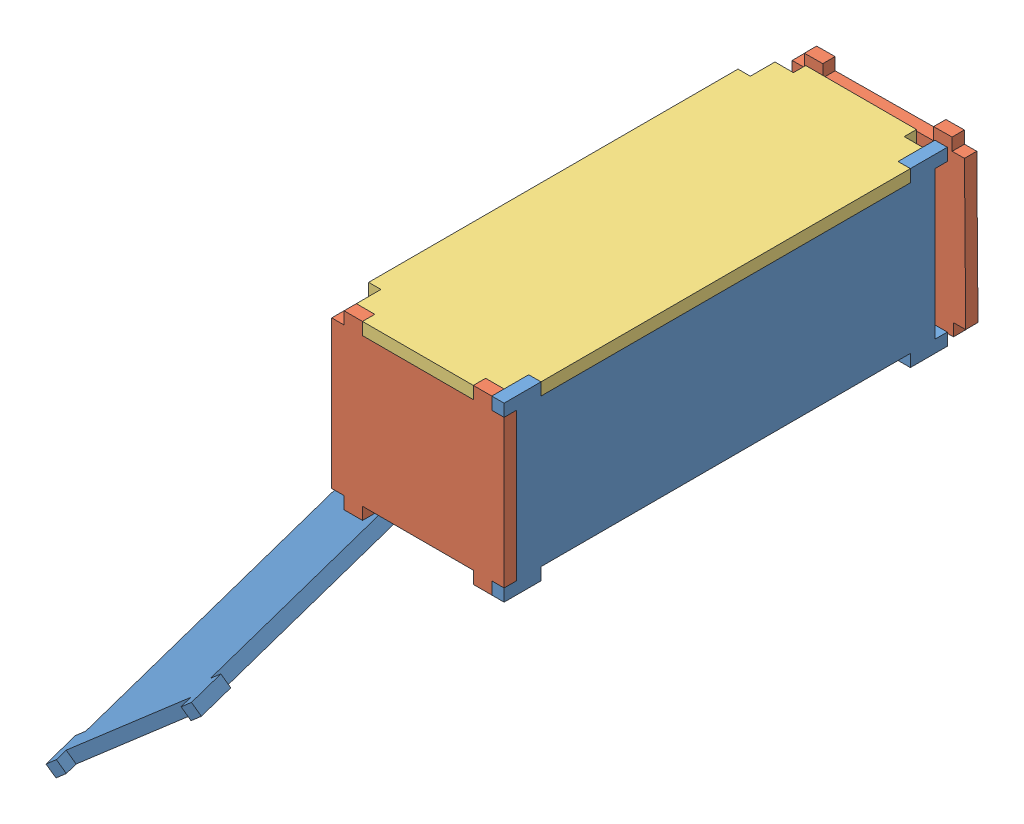
SolidWorks assembly box, configuration Default. Lengths in mm.
Overall size (296.97 308.69 766.09).
5 component instances, 3 part files, 3 mates.
Components (placement in the parent):
- side-1: side [Default] at origin size (12.7 177.8 457.2)
- endcaps-1: endcaps [Default] at (-165.1 0 215.9) size (177.8 177.8 12.7)
- bottom-1: bottom [Default] at (12.7 177.8 -201.2027) x (0 0 1) z (0 -1 0) size (457.2 177.8 12.7)
- endcaps-2: endcaps [Default] at (-6.2944 152.891 -277.8991) x (-0.999966 -0.00828 0) z (0 0 1) size (177.8 177.8 12.7)
- side-3: side [Default] at (-242.2582 -101.5718 264.35) x (0.62535 -0.758323 -0.184077) z (0.183799 -0.08612 0.979184) size (12.7 177.8 457.2)
Mates (geometry in assembly coordinates):
- Coincident9: coincident anti-aligned: plane of side-1 through (12.7 88.9 215.9) normal (0 0 1); plane of endcaps-1 through (-271.9214 88.9 215.9) normal (0 0 -1)
- Coincident11: coincident aligned: plane of side-1 through (12.7 88.9 -381.704) normal (1 0 0); plane of bottom-1 through (12.7 165.1 -381.704) normal (1 0 0)
- Parallel9: parallel aligned: plane of bottom-1 through (-76.2 165.1 -228.6) normal (0 0 -1); plane of endcaps-2 through (101.2594 64.8785 -277.8991) normal (0 0 -1)
